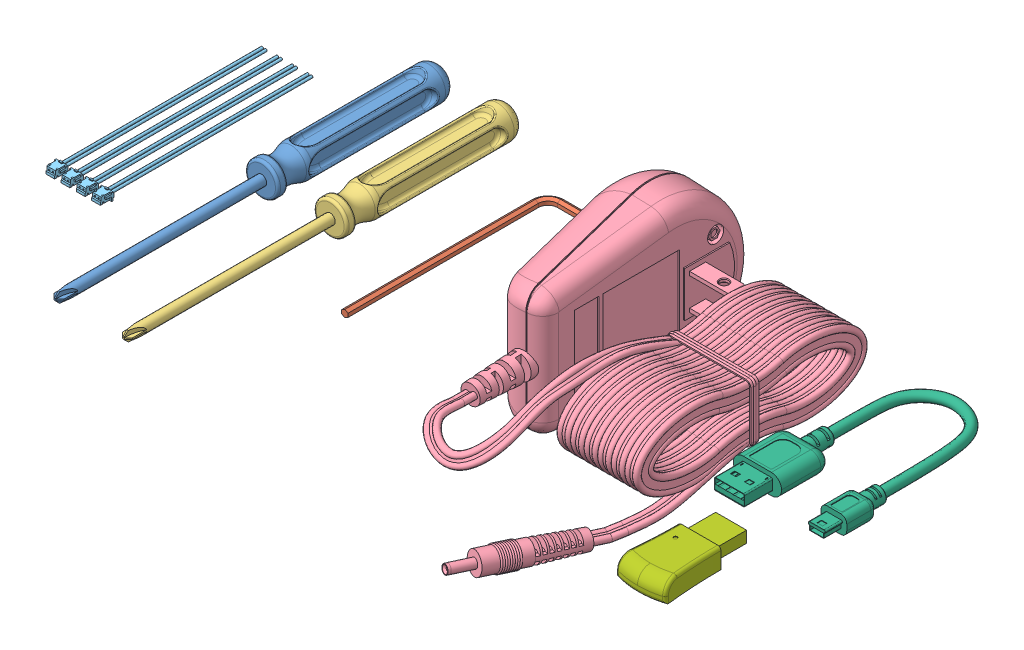
SolidWorks assembly accessories, configuration Default. Lengths in mm.
Overall size (280.09 361.61 207.63).
10 component instances, 7 part files, 8 mates.
Components (placement in the parent):
- Philips Screwdriver P2-1: Philips Screwdriver P2 [Default] at (-34.6747 -322 -64.6469) size (13.35 13.35 152.42)
- 2.5mm allan key-1: 2.5mm allan key [Default] at origin size (21.25 2.89 81.25)
- Philips Screwdriver P0-2: Philips Screwdriver P0 [Default] at (-7.9592 -322 -64.9694) size (13.35 13.35 152.42)
- 12v 1A DC power supply-1: 12v 1A DC power supply [Default] at (60 0 -78.443) x (0 0 1) z (-1 0 0) size (158.81 65.98 91.74)
- JST ZH 2-Pin Pigtail-1: JST ZH 2-Pin Pigtail [Default] at (-105.2005 -1.234 7.9753) size (4.5 3.4 84.2)
- mini usb cable-1: mini usb cable [Default] at (127.9449 -3.4917 -61.0519) x (0 0 -1) z (1 0 0) size (76.63 8 44.69)
- JST ZH 2-Pin Pigtail-2: JST ZH 2-Pin Pigtail [Default] at (-99.2005 -1.234 7.9753) size (4.5 3.4 84.2)
- JST ZH 2-Pin Pigtail-3: JST ZH 2-Pin Pigtail [Default] at (-93.2005 -1.234 7.9753) size (4.5 3.4 84.2)
- JST ZH 2-Pin Pigtail-4: JST ZH 2-Pin Pigtail [Default] at (-87.2005 -1.234 7.9753) size (4.5 3.4 84.2)
- Bluetooth Dongle-1: Bluetooth Dongle [Default] at (153.0572 3.8862 13.3433) x (1 0 0) z (0 1 0) size (19.76 36.91 8.21)
Mates (geometry in assembly coordinates):
- Coincident1: coincident aligned: plane of 2.5mm allan key-1 through (0 0 0) normal (0 0 1); plane of assembly through (0 0 0) normal (0 0 1)
- Coincident2: coincident aligned: plane of 2.5mm allan key-1 through (0 0 0) normal (0 1 0); plane of assembly through (0 0 0) normal (0 1 0)
- Coincident3: coincident aligned: plane of 2.5mm allan key-1 through (0 0 0) normal (1 0 0); plane of assembly through (0 0 0) normal (1 0 0)
- Distance2: distance = 322 mm aligned: plane of Philips Screwdriver P2-1 through (-34.6747 -322 -64.6469) normal (0 1 0); plane of assembly through (0 0 0) normal (0 1 0)
- Distance3: distance = 322 mm aligned: plane of Philips Screwdriver P0-2 through (-7.9592 -322 -64.9694) normal (0 1 0); plane of assembly through (0 0 0) normal (0 1 0)
- Coincident6: coincident aligned: plane of 12v 1A DC power supply-1; plane of assembly through (0 0 0) normal (0 1 0)
- Distance1: distance = 60 mm anti-aligned: plane of assembly through (0 0 0) normal (1 0 0); plane of 12v 1A DC power supply-1 through (60 0 -78.443) normal (-1 0 0)
- Coincident7: coincident anti-aligned: plane of Bluetooth Dongle-1 through (153.0572 0 4.9314) normal (0 -1 0); plane of assembly through (0 0 0) normal (0 1 0)
